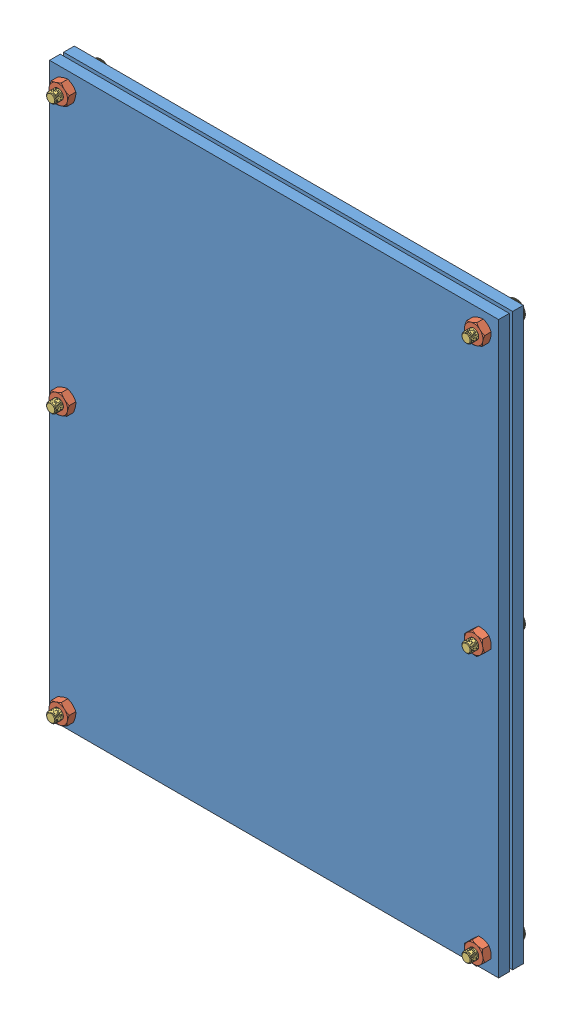
SolidWorks assembly mesh_divider_assem, configuration TwoThirds_Default. Lengths in mm.
Overall size (133.35 169.33 15.17).
14 component instances, 3 part files, 31 mates.
Components (placement in the parent):
- mesh_divider-1: mesh_divider [TwoThird_Default] at (51.4387 34.8533 172.5448) size (133.35 169.33 3.17)
- mesh_divider-2: mesh_divider [TwoThirds_FullCover] at (51.4387 34.8533 168.3698) size (133.35 169.33 3.17)
- M3_nut-1: M3_nut [91828A211] at (56.4387 199.1866 176.9198) x (0.304188 -0.952612 0) z (0 0 1) size (5.5 6.35 2.78)
- M3x12-1: M3x12 [90751A113] at (56.4387 199.1866 168.3698) size (5.5 5.5 15.17)
- M3x12-2: M3x12 [90751A113] at (179.7887 199.1866 168.3698) size (5.5 5.5 15.17)
- M3_nut-2: M3_nut [91828A211] at (179.7887 199.1866 176.9198) x (0.304188 -0.952612 0) z (0 0 1) size (5.5 6.35 2.78)
- M3_nut-3: M3_nut [91828A211] at (179.7887 39.8533 176.9198) x (0.304188 0.952612 0) z (0 0 1) size (5.5 6.35 2.78)
- M3x12-3: M3x12 [90751A113] at (179.7887 39.8533 168.3698) size (5.5 5.5 15.17)
- M3_nut-4: M3_nut [91828A211] at (56.4387 119.5199 176.9198) x (0.304188 -0.952612 0) z (0 0 1) size (5.5 6.35 2.78)
- M3x12-4: M3x12 [90751A113] at (56.4387 39.8533 168.3698) size (5.5 5.5 15.17)
- M3_nut-5: M3_nut [91828A211] at (179.7887 119.5199 176.9198) x (0.302917 0.953017 0) z (0 0 1) size (5.5 6.35 2.78)
- M3x12-5: M3x12 [90751A113] at (56.4387 119.5199 168.3698) size (5.5 5.5 15.17)
- M3_nut-6: M3_nut [91828A211] at (56.4387 39.8533 176.9198) x (0.304188 -0.952612 0) z (0 0 1) size (5.5 6.35 2.78)
- M3x12-6: M3x12 [90751A113] at (179.7887 119.5199 168.3698) size (5.5 5.5 15.17)
Mates (geometry in assembly coordinates):
- Distance1: distance = 1 mm anti-aligned: plane of mesh_divider-1 through (51.4387 34.8533 172.5448) normal (0 0 -1); plane of mesh_divider-2 through (51.4387 34.8533 171.5448) normal (0 0 1)
- Concentric1: concentric aligned: cylinder of mesh_divider-2 through (179.7887 199.1866 171.5448) axis (0 0 -1) radius 1.5; line of M3x12-2 through (179.7887 199.1866 181.0582) axis (0 0 -1)
- Coincident2: coincident anti-aligned: plane of mesh_divider-2 through (51.4387 34.8533 168.3698) normal (0 0 -1); plane of M3x12-2 through (179.7887 201.7716 168.3698) normal (0 0 1)
- Concentric2: concentric aligned: cylinder of mesh_divider-1 through (179.7887 199.1866 175.7198) axis (0 0 -1) radius 1.5; line of M3x12-2 through (179.7887 199.1866 181.0582) axis (0 0 -1)
- Screw1: screw = 1 aligned: line of M3x12-2 through (179.7887 199.1866 181.0582) axis (0 0 -1); circle of M3_nut-2
- Coincident3: coincident anti-aligned: plane of mesh_divider-1 through (51.4387 34.8533 175.7198) normal (0 0 1); plane of M3_nut-2 through (180.4647 202.2893 175.7198) normal (0 0 -1)
- Concentric3: concentric aligned: cylinder of mesh_divider-2 through (56.4387 199.1866 171.5448) axis (0 0 -1) radius 1.5; line of M3x12-1 through (56.4387 199.1866 181.0582) axis (0 0 -1)
- Coincident4: coincident anti-aligned: plane of mesh_divider-2 through (51.4387 34.8533 168.3698) normal (0 0 -1); plane of M3x12-1 through (56.4387 201.7716 168.3698) normal (0 0 1)
- Concentric4: concentric anti-aligned: circle of mesh_divider-1; line of M3x12-1 through (56.4387 199.1866 181.0582) axis (0 0 -1)
- Screw2: screw = 1 aligned: circle of M3_nut-1; line of M3x12-1 through (56.4387 199.1866 181.0582) axis (0 0 -1)
- Coincident5: coincident anti-aligned: plane of mesh_divider-1 through (51.4387 34.8533 175.7198) normal (0 0 1); plane of M3_nut-1 through (57.1147 202.2893 175.7198) normal (0 0 -1)
- Concentric5: concentric aligned: cylinder of mesh_divider-2 through (179.7887 39.8533 171.5448) axis (0 0 -1) radius 1.5; line of M3x12-3 through (179.7887 39.8533 181.0582) axis (0 0 -1)
- Concentric6: concentric aligned: cylinder of mesh_divider-1 through (179.7887 39.8533 175.7198) axis (0 0 -1) radius 1.5; line of M3x12-3 through (179.7887 39.8533 181.0582) axis (0 0 -1)
- Coincident6: coincident anti-aligned: plane of mesh_divider-2 through (51.4387 34.8533 168.3698) normal (0 0 -1); plane of M3x12-3 through (179.7887 42.4383 168.3698) normal (0 0 1)
- Screw3: screw = 1 aligned: circle of M3_nut-3; line of M3x12-3 through (179.7887 39.8533 181.0582) axis (0 0 -1)
- Coincident7: coincident anti-aligned: plane of mesh_divider-1 through (51.4387 34.8533 175.7198) normal (0 0 1); plane of M3_nut-3 through (177.4397 37.7166 175.7198) normal (0 0 -1)
- Concentric7: concentric aligned: cylinder of mesh_divider-2 through (56.4387 39.8533 171.5448) axis (0 0 -1) radius 1.5; line of M3x12-4 through (56.4387 39.8533 181.0582) axis (0 0 -1)
- Concentric8: concentric aligned: cylinder of mesh_divider-1 through (56.4387 39.8533 175.7198) axis (0 0 -1) radius 1.5; line of M3x12-4 through (56.4387 39.8533 181.0582) axis (0 0 -1)
- Coincident8: coincident anti-aligned: plane of mesh_divider-2 through (51.4387 34.8533 168.3698) normal (0 0 -1); plane of M3x12-4 through (56.4387 42.4383 168.3698) normal (0 0 1)
- Screw4: screw = 1 aligned: line of M3x12-4 through (56.4387 39.8533 181.0582) axis (0 0 -1); circle of M3_nut-6
- Coincident9: coincident anti-aligned: plane of mesh_divider-1 through (51.4387 34.8533 175.7198) normal (0 0 1); plane of M3_nut-6 through (57.1147 42.9559 175.7198) normal (0 0 -1)
- Concentric9: concentric aligned: cylinder of mesh_divider-2 through (56.4387 119.5199 171.5448) axis (0 0 -1) radius 1.5; line of M3x12-5 through (56.4387 119.5199 181.0582) axis (0 0 -1)
- Concentric10: concentric aligned: cylinder of mesh_divider-1 through (56.4387 119.5199 175.7198) axis (0 0 -1) radius 1.5; line of M3x12-5 through (56.4387 119.5199 181.0582) axis (0 0 -1)
- Coincident10: coincident anti-aligned: plane of mesh_divider-2 through (51.4387 34.8533 168.3698) normal (0 0 -1); plane of M3x12-5 through (56.4387 122.1049 168.3698) normal (0 0 1)
- Screw5: screw = 1 aligned: circle of M3_nut-4; line of M3x12-5 through (56.4387 119.5199 181.0582) axis (0 0 -1)
- Coincident11: coincident anti-aligned: plane of mesh_divider-1 through (51.4387 34.8533 175.7198) normal (0 0 1); plane of M3_nut-4 through (57.1147 122.6226 175.7198) normal (0 0 -1)
- Concentric11: concentric aligned: cylinder of mesh_divider-2 through (179.7887 119.5199 171.5448) axis (0 0 -1) radius 1.5; line of M3x12-6 through (179.7887 119.5199 181.0582) axis (0 0 -1)
- Concentric12: concentric aligned: cylinder of mesh_divider-1 through (179.7887 119.5199 175.7198) axis (0 0 -1) radius 1.5; line of M3x12-6 through (179.7887 119.5199 181.0582) axis (0 0 -1)
- Coincident12: coincident anti-aligned: plane of mesh_divider-2 through (51.4387 34.8533 168.3698) normal (0 0 -1); plane of M3x12-6 through (179.7887 122.1049 168.3698) normal (0 0 1)
- Screw6: screw = 50.8 aligned: circle of M3_nut-5; line of M3x12-6 through (179.7887 119.5199 181.0582) axis (0 0 -1)
- Coincident13: coincident anti-aligned: plane of mesh_divider-1 through (51.4387 34.8533 175.7198) normal (0 0 1); plane of M3_nut-5 through (177.4426 117.3801 175.7198) normal (0 0 -1)
